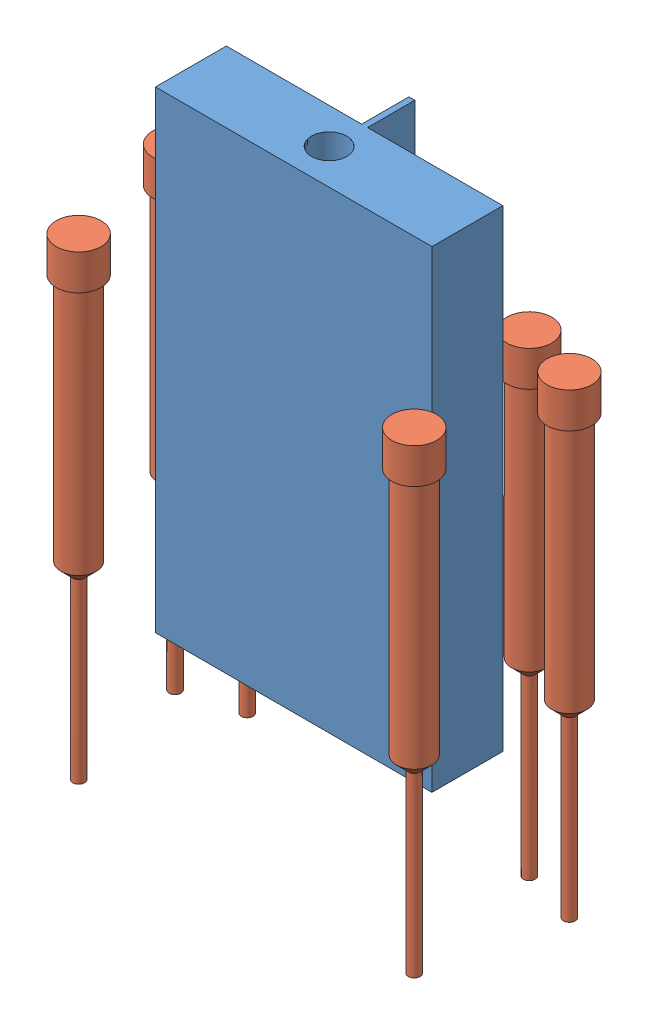
SolidWorks assembly Assem2, configuration Default. Lengths in mm.
Overall size (38.32 50 17.32).
7 component instances, 2 part files, 0 mates.
Components (placement in the parent):
- TOOL PUNCH 1.1-1: TOOL PUNCH 1.1 [Default] at (51.652 51.3518 69.766) x (-1 0 0) z (0 -1 0) size (23.4 10 40)
- TOOL PUNCH 1.2-3: TOOL PUNCH 1.2 [Default] at (37.452 1.3518 76.766) x (0.392959 0 0.919556) z (-0.919556 0 0.392959) size (3.8 40 3.8)
- TOOL PUNCH 1.2-4: TOOL PUNCH 1.2 [Default] at (34.967 1.3518 66.1224) x (0.644379 0 -0.764706) z (0.764706 0 0.644379) size (3.8 40 3.8)
- TOOL PUNCH 1.2-5: TOOL PUNCH 1.2 [Default] at (39.717 1.3518 64.766) x (0.83322 0 0.552941) z (-0.552941 0 0.83322) size (3.8 40 3.8)
- TOOL PUNCH 1.2-6: TOOL PUNCH 1.2 [Default] at (63.5871 1.3518 64.766) x (0.930199 0 -0.367055) z (0.367055 0 0.930199) size (3.8 40 3.8)
- TOOL PUNCH 1.2-7: TOOL PUNCH 1.2 [Default] at (68.3371 1.3518 66.1224) x (0.975189 0 0.221374) z (-0.221374 0 0.975189) size (3.8 40 3.8)
- TOOL PUNCH 1.2-8: TOOL PUNCH 1.2 [Default] at (65.852 1.3518 76.766) x (0.750606 0 0.66075) z (-0.66075 0 0.750606) size (3.8 40 3.8)
